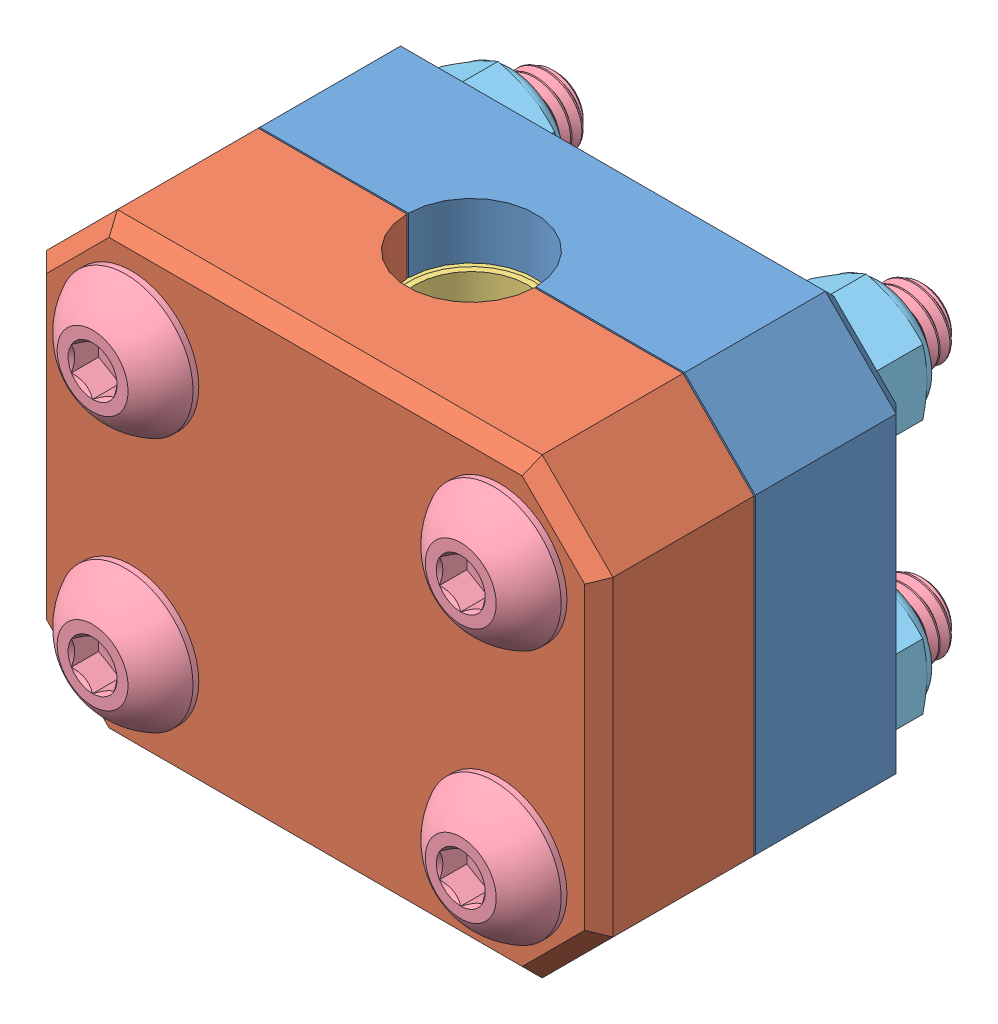
SolidWorks assembly Aft Linear Bearing Holder, configuration Default. Lengths in mm.
Overall size (123.48 58.99 97.2).
11 component instances, 5 part files, 0 mates.
Components (placement in the parent):
- Rudder Carriage Linear Bearing Holder Lower Shell-1: Rudder Carriage Linear Bearing Holder Lower Shell [Default] at origin size (40 32 10.95)
- Rudder Carriage Linear Bearing Holder Upper Shell-1: Rudder Carriage Linear Bearing Holder Upper Shell [Default] at origin size (123.48 58.99 77.75)
- LM8UU v2-1: LM8UU v2 [Default] at (-339.725 6533.262 2827.3504) size (14.96 23.84 14.96)
- 91239A236 - BHCS, M5-0.8 x 30mm, CLASS 10.9, BLACK-5: 91239A236 - BHCS, M5-0.8 x 30mm, CLASS 10.9, BLACK [91239A236] at (-352.725 6524.262 2841.1004) size (9.5 9.5 33.32)
- 91239A236 - BHCS, M5-0.8 x 30mm, CLASS 10.9, BLACK-6: 91239A236 - BHCS, M5-0.8 x 30mm, CLASS 10.9, BLACK [91239A236] at (-352.725 6542.262 2841.1004) size (9.5 9.5 33.32)
- 91239A236 - BHCS, M5-0.8 x 30mm, CLASS 10.9, BLACK-7: 91239A236 - BHCS, M5-0.8 x 30mm, CLASS 10.9, BLACK [91239A236] at (-326.725 6542.262 2841.1004) size (9.5 9.5 33.32)
- 91239A236 - BHCS, M5-0.8 x 30mm, CLASS 10.9, BLACK-4: 91239A236 - BHCS, M5-0.8 x 30mm, CLASS 10.9, BLACK [91239A236] at (-326.725 6524.262 2841.1004) size (9.5 9.5 33.32)
- 93625A200 - NUT, M5-0.8, NYLOC, 18-8-3: 93625A200 - NUT, M5-0.8, NYLOC, 18-8 [93625A200] at (-352.725 6542.262 2816.3504) x (1 0 0) z (0 1 0) size (8 5.15 9.24)
- 93625A200 - NUT, M5-0.8, NYLOC, 18-8-2: 93625A200 - NUT, M5-0.8, NYLOC, 18-8 [93625A200] at (-326.725 6542.262 2816.3504) x (1 0 0) z (0 1 0) size (8 5.15 9.24)
- 93625A200 - NUT, M5-0.8, NYLOC, 18-8-5: 93625A200 - NUT, M5-0.8, NYLOC, 18-8 [93625A200] at (-326.725 6524.262 2816.3504) x (1 0 0) z (0 1 0) size (8 5.15 9.24)
- 93625A200 - NUT, M5-0.8, NYLOC, 18-8-4: 93625A200 - NUT, M5-0.8, NYLOC, 18-8 [93625A200] at (-352.725 6524.262 2816.3504) x (1 0 0) z (0 1 0) size (8 5.15 9.24)
